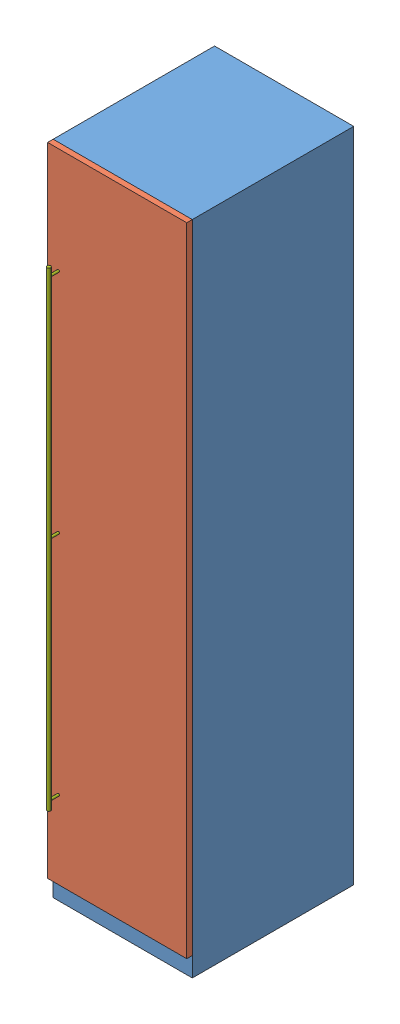
SolidWorks assembly PAX-Eingang, configuration Standard. Lengths in mm.
Overall size (500 2360 641).
9 component instances, 7 part files, 25 mates.
Components (placement in the parent):
- Pax-Korpus-Kleiderschrank-236-1: Pax-Korpus-Kleiderschrank-236 [Standard] at (-247.5936 -1124.7676 2360) size (500 2360 580)
- BALLSTAD-Tür-229-1: BALLSTAD-Tür-229 [Standard] at (-247.5936 90.2324 2650) size (500 2290 20)
- KOMPLEMENT-Regalbode-1: KOMPLEMENT-Regalbode [Standard] at (-247.5936 895.2324 2365) size (480 10 570)
- KOMPLEMENT-Kleiderstange-1: KOMPLEMENT-Kleiderstange [Standard] at (-487.5936 830.2324 2335) size (480 50 30)
- KOMPLEMENT-Regalbode-2: KOMPLEMENT-Regalbode [Standard] at (-247.5936 -434.7676 2365) size (480 10 570)
- KOMPLIMENT-Schublade-1: KOMPLIMENT-Schublade [Standard] at (-247.5936 -604.7676 2365) size (480 160 570)
- KOMPLEMENT-Netzdrahtkorb-1: KOMPLEMENT-Netzdrahtkorb [Standard] at (-247.5936 -894.7676 2365) size (480 160 570)
- KOMPLEMENT-Regalbode-3: KOMPLEMENT-Regalbode [Standard] at (-247.5936 -274.7676 2365) size (480 10 570)
- LANSA-1: LANSA [Standard] at (-458.5936 -804.7676 2704.5) x (0 0 -1) z (1 0 0) size (41 1690 13)
Mates (geometry in assembly coordinates):
- Deckungsgleich1: coincident aligned: plane of Pax-Korpus-Kleiderschrank-236-1 through (-247.5936 1235.2324 2360) normal (0 1 0); plane of BALLSTAD-Tür-229-1 through (-497.5936 1235.2324 2670) normal (0 1 0)
- Deckungsgleich2: coincident anti-aligned: plane of Pax-Korpus-Kleiderschrank-236-1 through (-497.5936 -1114.7676 2650) normal (0 0 1); plane of BALLSTAD-Tür-229-1 through (-247.5936 90.2324 2650) normal (0 0 -1)
- Deckungsgleich3: coincident aligned: plane of Pax-Korpus-Kleiderschrank-236-1 through (-497.5936 -1114.7676 2650) normal (-1 0 0); plane of BALLSTAD-Tür-229-1 through (-497.5936 -1054.7676 2670) normal (-1 0 0)
- Deckungsgleich4: coincident anti-aligned: plane of Pax-Korpus-Kleiderschrank-236-1 through (-487.5936 1225.2324 2080) normal (0 0 1); plane of KOMPLEMENT-Regalbode-1 through (-487.5936 905.2324 2080) normal (0 0 -1)
- Deckungsgleich5: coincident anti-aligned: plane of Pax-Korpus-Kleiderschrank-236-1 through (-487.5936 1225.2324 2650) normal (1 0 0); plane of KOMPLEMENT-Regalbode-1 through (-487.5936 905.2324 2650) normal (-1 0 0)
- Abstand1: distance = 320 mm anti-aligned: plane of KOMPLEMENT-Regalbode-1 through (-247.5936 905.2324 2365) normal (0 1 0); plane of Pax-Korpus-Kleiderschrank-236-1 through (-247.5936 1225.2324 2360) normal (0 -1 0)
- Deckungsgleich7: coincident anti-aligned: plane of Pax-Korpus-Kleiderschrank-236-1 through (-487.5936 1225.2324 2650) normal (1 0 0); plane of KOMPLEMENT-Kleiderstange-1 through (-487.5936 830.2324 2335) normal (-1 0 0)
- Abstand2: distance = 50 mm anti-aligned: plane of KOMPLEMENT-Kleiderstange-1 through (-467.5936 845.2324 2320) normal (0 1 0); plane of KOMPLEMENT-Regalbode-1 through (-247.5936 895.2324 2365) normal (0 -1 0)
- Abstand3: distance = 300 mm aligned: plane of KOMPLEMENT-Kleiderstange-1 through (-467.5936 795.2324 2350) normal (0 0 1); plane of Pax-Korpus-Kleiderschrank-236-1 through (-497.5936 -1114.7676 2650) normal (0 0 1)
- Deckungsgleich10: coincident anti-aligned: plane of Pax-Korpus-Kleiderschrank-236-1 through (-487.5936 1225.2324 2080) normal (0 0 1); plane of KOMPLEMENT-Regalbode-2 through (-487.5936 -424.7676 2080) normal (0 0 -1)
- Deckungsgleich11: coincident: plane of Pax-Korpus-Kleiderschrank-236-1 through (-487.5936 1225.2324 2650) normal (1 0 0); plane of KOMPLEMENT-Regalbode-2 through (-487.5936 -424.7676 2650) normal (-1 0 0)
- Abstand4: distance = 1220 mm anti-aligned: plane of KOMPLEMENT-Kleiderstange-1 through (-467.5936 795.2324 2320) normal (0 -1 0); plane of KOMPLEMENT-Regalbode-2 through (-247.5936 -424.7676 2365) normal (0 1 0)
- Deckungsgleich13: coincident anti-aligned: plane of Pax-Korpus-Kleiderschrank-236-1 through (-487.5936 1225.2324 2080) normal (0 0 1); plane of KOMPLIMENT-Schublade-1 through (-487.5936 -594.7676 2080) normal (0 0 -1)
- Deckungsgleich14: coincident anti-aligned: plane of Pax-Korpus-Kleiderschrank-236-1 through (-487.5936 1225.2324 2650) normal (1 0 0); plane of KOMPLIMENT-Schublade-1 through (-487.5936 -594.7676 2650) normal (-1 0 0)
- Abstand5: distance = 10 mm anti-aligned: plane of KOMPLIMENT-Schublade-1 through (-247.5936 -444.7676 2365) normal (0 1 0); plane of KOMPLEMENT-Regalbode-2 through (-247.5936 -434.7676 2365) normal (0 -1 0)
- Deckungsgleich16: coincident anti-aligned: plane of Pax-Korpus-Kleiderschrank-236-1 through (-247.5936 -1054.7676 2360) normal (0 1 0); plane of KOMPLEMENT-Netzdrahtkorb-1 through (-247.5936 -1054.7676 2365) normal (0 -1 0)
- Deckungsgleich17: coincident: plane of Pax-Korpus-Kleiderschrank-236-1 through (-487.5936 1225.2324 2650) normal (1 0 0); line of KOMPLEMENT-Netzdrahtkorb-1 through (-487.5936 -894.7676 2080) axis (0 0 1)
- Deckungsgleich18: coincident: plane of Pax-Korpus-Kleiderschrank-236-1 through (-487.5936 1225.2324 2080) normal (0 0 1); line of KOMPLEMENT-Netzdrahtkorb-1 through (-7.5936 -894.7676 2080) axis (-1 0 0)
- Deckungsgleich19: coincident anti-aligned: plane of Pax-Korpus-Kleiderschrank-236-1 through (-7.5936 1225.2324 2080) normal (-1 0 0); plane of KOMPLEMENT-Regalbode-3 through (-7.5936 -264.7676 2650) normal (1 0 0)
- Deckungsgleich20: coincident anti-aligned: plane of Pax-Korpus-Kleiderschrank-236-1 through (-487.5936 1225.2324 2080) normal (0 0 1); plane of KOMPLEMENT-Regalbode-3 through (-487.5936 -264.7676 2080) normal (0 0 -1)
- Abstand7: distance = 150 mm anti-aligned: plane of KOMPLEMENT-Regalbode-3 through (-247.5936 -274.7676 2365) normal (0 -1 0); plane of KOMPLEMENT-Regalbode-2 through (-247.5936 -424.7676 2365) normal (0 1 0)
- Deckungsgleich21: coincident anti-aligned: plane of BALLSTAD-Tür-229-1 through (-247.5936 90.2324 2670) normal (0 0 1); plane of LANSA-1 through (-458.5936 855.2324 2670) normal (0 0 -1)
- Parallel1: parallel aligned: line of BALLSTAD-Tür-229-1 through (-497.5936 1235.2324 2670) axis (0 -1 0); cylinder of LANSA-1 through (-458.5936 885.2324 2704.5) axis (0 -1 0) radius 6.5
- Abstand8: distance = 250 mm aligned: plane of LANSA-1 through (-458.5936 -804.7676 2704.5) normal (0 -1 0); plane of BALLSTAD-Tür-229-1 through (-497.5936 -1054.7676 2670) normal (0 -1 0)
- Abstand9: distance = 35 mm: cylinder of LANSA-1 through (-458.5936 -774.7676 2670) axis (0 0 1) radius 4; line of BALLSTAD-Tür-229-1 through (-497.5936 1235.2324 2670) axis (0 -1 0)
